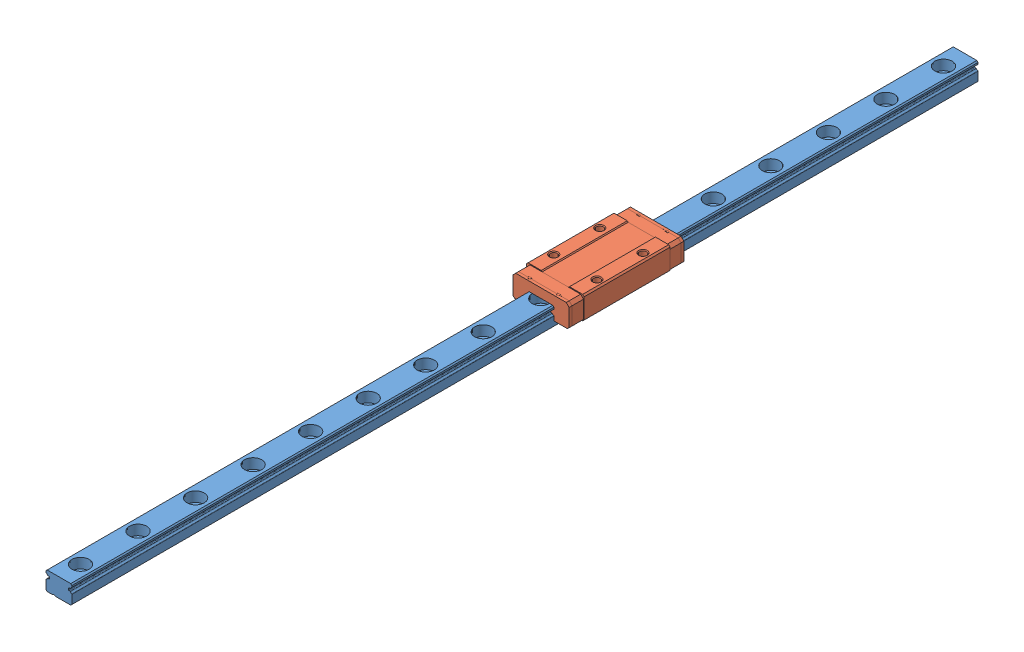
SolidWorks assembly MGNR9R_with_MGN9HZFC_Carriage, configuration Default. Lengths in mm.
Overall size (20 10 315).
2 component instances, 2 part files, 5 mates.
Components (placement in the parent):
- MGNR9R-1: MGNR9R [315mm Long] at origin size (9 6.5 315)
- MGN9HZFC_Carriage-1: MGN9HZFC_Carriage [Default] at (0 -4.5 -10.0679) x (0 0 -1) z (0 1 0) size (39.9 20 8)
Mates (geometry in assembly coordinates):
- Coincident1: coincident aligned: plane of MGNR9R-1 through (0 0 0) normal (0 0 1); plane of assembly through (0 0 0) normal (0 0 1)
- Coincident2: coincident aligned: plane of MGNR9R-1 through (0 0 0) normal (0 1 0); plane of assembly through (0 0 0) normal (0 1 0)
- Coincident3: coincident aligned: plane of MGNR9R-1 through (0 0 0) normal (1 0 0); plane of assembly through (0 0 0) normal (1 0 0)
- Coincident4: coincident anti-aligned: plane of MGNR9R-1 through (0 -2 0) normal (0 -1 0); plane of MGN9HZFC_Carriage-1 through (0 -2 -10.0679) normal (0 1 0)
- Coincident5: coincident anti-aligned: plane of MGNR9R-1 through (0 0 0) normal (1 0 0); plane of MGN9HZFC_Carriage-1
